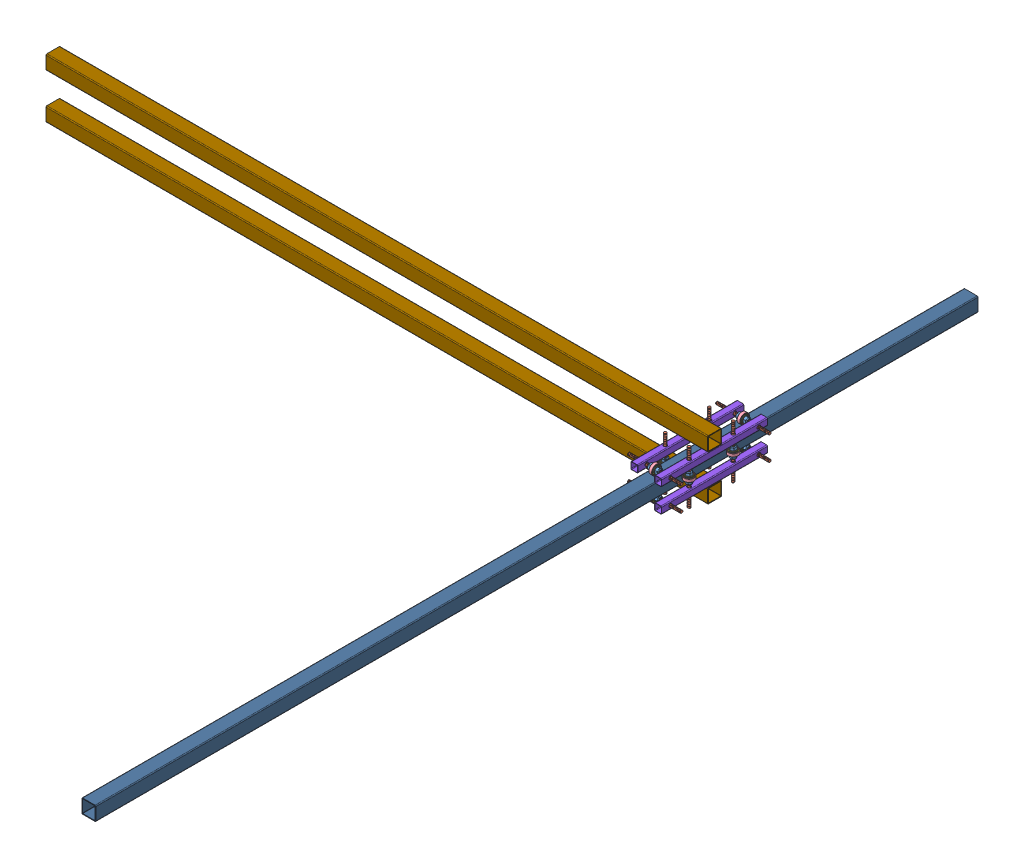
SolidWorks assembly CNC_SubAssembly1, configuration Default. Lengths in mm.
Overall size (1525 134 2000).
159 component instances, 10 part files, 35 mates.
Components (placement in the parent):
- BB_Rod_Assembly-1: BB_Rod_Assembly [Default] at (27 -60 -333.8942) x (-0.532809 0 0.846236) z (-0.846236 0 -0.532809) size (23.24 121.11 23.24)
  - M8_self_lock_Nut-1: M8_self_lock_Nut [Valor predeterminado] at (0 71 0) x (-0.837169 0 -0.546944) z (0 -1 0) size (15.1 12 8.06)
  - M8_Threaded_Rod-1: M8_Threaded_Rod [Default] at origin size (6.18 121.11 6.93)
  - M8_Washer-1: M8_Washer [Default] at (0 63.5 0) x (1 0 0) z (0 1 0) size (15.5 15.5 1.5)
  - BB_Assembly-1: BB_Assembly [Default] at (0 60 0) x (0 -1 0) z (-0.058052 0 0.998314) size (7 22 22)
    - BB_OuterRing-1: BB_OuterRing [Default] at origin size (7 22 22)
    - BB_InnerRing-1: BB_InnerRing [Default] x (1 0 0) z (0 0.97954 -0.20125) size (7 13 13)
    - BB_Ball-1: BB_Ball [Default] at (0 1.61 7.8363) x (-1 0 0) z (0 -0.97954 0.20125) size (4.5 4.5 4.5)
    - BB_Cage-1: BB_Cage [Default] x (0 -0.20125 -0.97954) z (1 0 0) size (18 18 2.77)
    - BB_Ball-2: BB_Ball [Default] at (0 6.6796 4.4027) x (-1 0 0) z (0 -0.550334 0.834945) size (4.5 4.5 4.5)
    - BB_Ball-3: BB_Ball [Default] at (0 7.8363 -1.61) x (-1 0 0) z (0 0.20125 0.97954) size (4.5 4.5 4.5)
    - BB_Ball-4: BB_Ball [Default] at (0 4.4027 -6.6796) x (-1 0 0) z (0 0.834945 0.550334) size (4.5 4.5 4.5)
    - BB_Ball-5: BB_Ball [Default] at (0 -1.61 -7.8363) x (-1 0 0) z (0 0.97954 -0.20125) size (4.5 4.5 4.5)
    - BB_Ball-6: BB_Ball [Default] at (0 -6.6796 -4.4027) x (-1 0 0) z (0 0.550334 -0.834945) size (4.5 4.5 4.5)
    - BB_Ball-7: BB_Ball [Default] at (0 -7.8363 1.61) x (-1 0 0) z (0 -0.20125 -0.97954) size (4.5 4.5 4.5)
    - BB_Ball-8: BB_Ball [Default] at (0 -4.4027 6.6796) x (-1 0 0) z (0 -0.834945 -0.550334) size (4.5 4.5 4.5)
    - BB_Cage-2: BB_Cage [Default] x (0 0.20125 0.97954) z (-1 0 0) size (18 18 2.77)
  - M8_Washer-3: M8_Washer [Default] at (0 55 0) x (1 0 0) z (0 1 0) size (15.5 15.5 1.5)
  - M8_self_lock_Nut-15: M8_self_lock_Nut [Valor predeterminado] at (0 49 0) x (1 0 0) z (0 1 0) size (15.1 12 8.06)
- Square_Tubing_16mm-1: Square_Tubing_16mm [Default] at (27 27 -383.8942) size (16 16 240)
- BB_Rod_Assembly-2: BB_Rod_Assembly [Default] at (27 -60 -433.8942) x (0.999895 0 -0.014471) z (0.014471 0 0.999895) size (23.24 121.11 23.24)
  - M8_self_lock_Nut-1: M8_self_lock_Nut [Valor predeterminado] at (0 71 0) x (-0.837169 0 -0.546944) z (0 -1 0) size (15.1 12 8.06)
  - M8_Threaded_Rod-1: M8_Threaded_Rod [Default] at origin size (6.18 121.11 6.93)
  - M8_Washer-1: M8_Washer [Default] at (0 63.5 0) x (1 0 0) z (0 1 0) size (15.5 15.5 1.5)
  - BB_Assembly-1: BB_Assembly [Default] at (0 60 0) x (0 -1 0) z (-0.058052 0 0.998314) size (7 22 22)
    - BB_OuterRing-1: BB_OuterRing [Default] at origin size (7 22 22)
    - BB_InnerRing-1: BB_InnerRing [Default] x (1 0 0) z (0 0.97954 -0.20125) size (7 13 13)
    - BB_Ball-1: BB_Ball [Default] at (0 1.61 7.8363) x (-1 0 0) z (0 -0.97954 0.20125) size (4.5 4.5 4.5)
    - BB_Cage-1: BB_Cage [Default] x (0 -0.20125 -0.97954) z (1 0 0) size (18 18 2.77)
    - BB_Ball-2: BB_Ball [Default] at (0 6.6796 4.4027) x (-1 0 0) z (0 -0.550334 0.834945) size (4.5 4.5 4.5)
    - BB_Ball-3: BB_Ball [Default] at (0 7.8363 -1.61) x (-1 0 0) z (0 0.20125 0.97954) size (4.5 4.5 4.5)
    - BB_Ball-4: BB_Ball [Default] at (0 4.4027 -6.6796) x (-1 0 0) z (0 0.834945 0.550334) size (4.5 4.5 4.5)
    - BB_Ball-5: BB_Ball [Default] at (0 -1.61 -7.8363) x (-1 0 0) z (0 0.97954 -0.20125) size (4.5 4.5 4.5)
    - BB_Ball-6: BB_Ball [Default] at (0 -6.6796 -4.4027) x (-1 0 0) z (0 0.550334 -0.834945) size (4.5 4.5 4.5)
    - BB_Ball-7: BB_Ball [Default] at (0 -7.8363 1.61) x (-1 0 0) z (0 -0.20125 -0.97954) size (4.5 4.5 4.5)
    - BB_Ball-8: BB_Ball [Default] at (0 -4.4027 6.6796) x (-1 0 0) z (0 -0.834945 -0.550334) size (4.5 4.5 4.5)
    - BB_Cage-2: BB_Cage [Default] x (0 0.20125 0.97954) z (-1 0 0) size (18 18 2.77)
  - M8_Washer-3: M8_Washer [Default] at (0 55 0) x (1 0 0) z (0 1 0) size (15.5 15.5 1.5)
  - M8_self_lock_Nut-15: M8_self_lock_Nut [Valor predeterminado] at (0 49 0) x (1 0 0) z (0 1 0) size (15.1 12 8.06)
- Square_Tubing_16mm-2: Square_Tubing_16mm [Default] at (27 -27 -383.8942) size (16 16 240)
- BB_Rod_Assembly-3: BB_Rod_Assembly [Default] at (-60 27 -483.8942) x (0 -0.853939 -0.520374) z (0 -0.520374 0.853939) size (23.24 121.11 23.24)
  - M8_self_lock_Nut-1: M8_self_lock_Nut [Valor predeterminado] at (0 71 0) x (-0.837169 0 -0.546944) z (0 -1 0) size (15.1 12 8.06)
  - M8_Threaded_Rod-1: M8_Threaded_Rod [Default] at origin size (6.18 121.11 6.93)
  - M8_Washer-1: M8_Washer [Default] at (0 63.5 0) x (1 0 0) z (0 1 0) size (15.5 15.5 1.5)
  - BB_Assembly-1: BB_Assembly [Default] at (0 60 0) x (0 -1 0) z (-0.058052 0 0.998314) size (7 22 22)
    - BB_OuterRing-1: BB_OuterRing [Default] at origin size (7 22 22)
    - BB_InnerRing-1: BB_InnerRing [Default] x (1 0 0) z (0 0.97954 -0.20125) size (7 13 13)
    - BB_Ball-1: BB_Ball [Default] at (0 1.61 7.8363) x (-1 0 0) z (0 -0.97954 0.20125) size (4.5 4.5 4.5)
    - BB_Cage-1: BB_Cage [Default] x (0 -0.20125 -0.97954) z (1 0 0) size (18 18 2.77)
    - BB_Ball-2: BB_Ball [Default] at (0 6.6796 4.4027) x (-1 0 0) z (0 -0.550334 0.834945) size (4.5 4.5 4.5)
    - BB_Ball-3: BB_Ball [Default] at (0 7.8363 -1.61) x (-1 0 0) z (0 0.20125 0.97954) size (4.5 4.5 4.5)
    - BB_Ball-4: BB_Ball [Default] at (0 4.4027 -6.6796) x (-1 0 0) z (0 0.834945 0.550334) size (4.5 4.5 4.5)
    - BB_Ball-5: BB_Ball [Default] at (0 -1.61 -7.8363) x (-1 0 0) z (0 0.97954 -0.20125) size (4.5 4.5 4.5)
    - BB_Ball-6: BB_Ball [Default] at (0 -6.6796 -4.4027) x (-1 0 0) z (0 0.550334 -0.834945) size (4.5 4.5 4.5)
    - BB_Ball-7: BB_Ball [Default] at (0 -7.8363 1.61) x (-1 0 0) z (0 -0.20125 -0.97954) size (4.5 4.5 4.5)
    - BB_Ball-8: BB_Ball [Default] at (0 -4.4027 6.6796) x (-1 0 0) z (0 -0.834945 -0.550334) size (4.5 4.5 4.5)
    - BB_Cage-2: BB_Cage [Default] x (0 0.20125 0.97954) z (-1 0 0) size (18 18 2.77)
  - M8_Washer-3: M8_Washer [Default] at (0 55 0) x (1 0 0) z (0 1 0) size (15.5 15.5 1.5)
  - M8_self_lock_Nut-15: M8_self_lock_Nut [Valor predeterminado] at (0 49 0) x (1 0 0) z (0 1 0) size (15.1 12 8.06)
- BB_Rod_Assembly-4: BB_Rod_Assembly [Default] at (-60 27 -283.8942) x (0 -0.092758 0.995689) z (0 0.995689 0.092758) size (23.24 121.11 23.24)
  - M8_self_lock_Nut-1: M8_self_lock_Nut [Valor predeterminado] at (0 71 0) x (-0.837169 0 -0.546944) z (0 -1 0) size (15.1 12 8.06)
  - M8_Threaded_Rod-1: M8_Threaded_Rod [Default] at origin size (6.18 121.11 6.93)
  - M8_Washer-1: M8_Washer [Default] at (0 63.5 0) x (1 0 0) z (0 1 0) size (15.5 15.5 1.5)
  - BB_Assembly-1: BB_Assembly [Default] at (0 60 0) x (0 -1 0) z (-0.058052 0 0.998314) size (7 22 22)
    - BB_OuterRing-1: BB_OuterRing [Default] at origin size (7 22 22)
    - BB_InnerRing-1: BB_InnerRing [Default] x (1 0 0) z (0 0.97954 -0.20125) size (7 13 13)
    - BB_Ball-1: BB_Ball [Default] at (0 1.61 7.8363) x (-1 0 0) z (0 -0.97954 0.20125) size (4.5 4.5 4.5)
    - BB_Cage-1: BB_Cage [Default] x (0 -0.20125 -0.97954) z (1 0 0) size (18 18 2.77)
    - BB_Ball-2: BB_Ball [Default] at (0 6.6796 4.4027) x (-1 0 0) z (0 -0.550334 0.834945) size (4.5 4.5 4.5)
    - BB_Ball-3: BB_Ball [Default] at (0 7.8363 -1.61) x (-1 0 0) z (0 0.20125 0.97954) size (4.5 4.5 4.5)
    - BB_Ball-4: BB_Ball [Default] at (0 4.4027 -6.6796) x (-1 0 0) z (0 0.834945 0.550334) size (4.5 4.5 4.5)
    - BB_Ball-5: BB_Ball [Default] at (0 -1.61 -7.8363) x (-1 0 0) z (0 0.97954 -0.20125) size (4.5 4.5 4.5)
    - BB_Ball-6: BB_Ball [Default] at (0 -6.6796 -4.4027) x (-1 0 0) z (0 0.550334 -0.834945) size (4.5 4.5 4.5)
    - BB_Ball-7: BB_Ball [Default] at (0 -7.8363 1.61) x (-1 0 0) z (0 -0.20125 -0.97954) size (4.5 4.5 4.5)
    - BB_Ball-8: BB_Ball [Default] at (0 -4.4027 6.6796) x (-1 0 0) z (0 -0.834945 -0.550334) size (4.5 4.5 4.5)
    - BB_Cage-2: BB_Cage [Default] x (0 0.20125 0.97954) z (-1 0 0) size (18 18 2.77)
  - M8_Washer-3: M8_Washer [Default] at (0 55 0) x (1 0 0) z (0 1 0) size (15.5 15.5 1.5)
  - M8_self_lock_Nut-15: M8_self_lock_Nut [Valor predeterminado] at (0 49 0) x (1 0 0) z (0 1 0) size (15.1 12 8.06)
- Square_Tubing_16mm-3: Square_Tubing_16mm [Default] at (-27 -27 -383.8942) size (16 16 240)
- Square_Tubing_16mm-4: Square_Tubing_16mm [Default] at (-27 27 -383.8942) size (16 16 240)
- BB_Rod_Assembly-5: BB_Rod_Assembly [Default] at (-60 -27 -483.8942) x (0 -1 0) z (0 0 1) size (23.24 121.11 23.24)
  - M8_self_lock_Nut-1: M8_self_lock_Nut [Valor predeterminado] at (0 71 0) x (-0.837169 0 -0.546944) z (0 -1 0) size (15.1 12 8.06)
  - M8_Threaded_Rod-1: M8_Threaded_Rod [Default] at origin size (6.18 121.11 6.93)
  - M8_Washer-1: M8_Washer [Default] at (0 63.5 0) x (1 0 0) z (0 1 0) size (15.5 15.5 1.5)
  - BB_Assembly-1: BB_Assembly [Default] at (0 60 0) x (0 -1 0) z (-0.058052 0 0.998314) size (7 22 22)
    - BB_OuterRing-1: BB_OuterRing [Default] at origin size (7 22 22)
    - BB_InnerRing-1: BB_InnerRing [Default] x (1 0 0) z (0 0.97954 -0.20125) size (7 13 13)
    - BB_Ball-1: BB_Ball [Default] at (0 1.61 7.8363) x (-1 0 0) z (0 -0.97954 0.20125) size (4.5 4.5 4.5)
    - BB_Cage-1: BB_Cage [Default] x (0 -0.20125 -0.97954) z (1 0 0) size (18 18 2.77)
    - BB_Ball-2: BB_Ball [Default] at (0 6.6796 4.4027) x (-1 0 0) z (0 -0.550334 0.834945) size (4.5 4.5 4.5)
    - BB_Ball-3: BB_Ball [Default] at (0 7.8363 -1.61) x (-1 0 0) z (0 0.20125 0.97954) size (4.5 4.5 4.5)
    - BB_Ball-4: BB_Ball [Default] at (0 4.4027 -6.6796) x (-1 0 0) z (0 0.834945 0.550334) size (4.5 4.5 4.5)
    - BB_Ball-5: BB_Ball [Default] at (0 -1.61 -7.8363) x (-1 0 0) z (0 0.97954 -0.20125) size (4.5 4.5 4.5)
    - BB_Ball-6: BB_Ball [Default] at (0 -6.6796 -4.4027) x (-1 0 0) z (0 0.550334 -0.834945) size (4.5 4.5 4.5)
    - BB_Ball-7: BB_Ball [Default] at (0 -7.8363 1.61) x (-1 0 0) z (0 -0.20125 -0.97954) size (4.5 4.5 4.5)
    - BB_Ball-8: BB_Ball [Default] at (0 -4.4027 6.6796) x (-1 0 0) z (0 -0.834945 -0.550334) size (4.5 4.5 4.5)
    - BB_Cage-2: BB_Cage [Default] x (0 0.20125 0.97954) z (-1 0 0) size (18 18 2.77)
  - M8_Washer-3: M8_Washer [Default] at (0 55 0) x (1 0 0) z (0 1 0) size (15.5 15.5 1.5)
  - M8_self_lock_Nut-15: M8_self_lock_Nut [Valor predeterminado] at (0 49 0) x (1 0 0) z (0 1 0) size (15.1 12 8.06)
- BB_Rod_Assembly-6: BB_Rod_Assembly [Default] at (-27 -60 -333.8942) x (0.666967 0 -0.745087) z (0.745087 0 0.666967) size (23.24 121.11 23.24)
  - M8_self_lock_Nut-1: M8_self_lock_Nut [Valor predeterminado] at (0 71 0) x (-0.837169 0 -0.546944) z (0 -1 0) size (15.1 12 8.06)
  - M8_Threaded_Rod-1: M8_Threaded_Rod [Default] at origin size (6.18 121.11 6.93)
  - M8_Washer-1: M8_Washer [Default] at (0 63.5 0) x (1 0 0) z (0 1 0) size (15.5 15.5 1.5)
  - BB_Assembly-1: BB_Assembly [Default] at (0 60 0) x (0 -1 0) z (-0.058052 0 0.998314) size (7 22 22)
    - BB_OuterRing-1: BB_OuterRing [Default] at origin size (7 22 22)
    - BB_InnerRing-1: BB_InnerRing [Default] x (1 0 0) z (0 0.97954 -0.20125) size (7 13 13)
    - BB_Ball-1: BB_Ball [Default] at (0 1.61 7.8363) x (-1 0 0) z (0 -0.97954 0.20125) size (4.5 4.5 4.5)
    - BB_Cage-1: BB_Cage [Default] x (0 -0.20125 -0.97954) z (1 0 0) size (18 18 2.77)
    - BB_Ball-2: BB_Ball [Default] at (0 6.6796 4.4027) x (-1 0 0) z (0 -0.550334 0.834945) size (4.5 4.5 4.5)
    - BB_Ball-3: BB_Ball [Default] at (0 7.8363 -1.61) x (-1 0 0) z (0 0.20125 0.97954) size (4.5 4.5 4.5)
    - BB_Ball-4: BB_Ball [Default] at (0 4.4027 -6.6796) x (-1 0 0) z (0 0.834945 0.550334) size (4.5 4.5 4.5)
    - BB_Ball-5: BB_Ball [Default] at (0 -1.61 -7.8363) x (-1 0 0) z (0 0.97954 -0.20125) size (4.5 4.5 4.5)
    - BB_Ball-6: BB_Ball [Default] at (0 -6.6796 -4.4027) x (-1 0 0) z (0 0.550334 -0.834945) size (4.5 4.5 4.5)
    - BB_Ball-7: BB_Ball [Default] at (0 -7.8363 1.61) x (-1 0 0) z (0 -0.20125 -0.97954) size (4.5 4.5 4.5)
    - BB_Ball-8: BB_Ball [Default] at (0 -4.4027 6.6796) x (-1 0 0) z (0 -0.834945 -0.550334) size (4.5 4.5 4.5)
    - BB_Cage-2: BB_Cage [Default] x (0 0.20125 0.97954) z (-1 0 0) size (18 18 2.77)
  - M8_Washer-3: M8_Washer [Default] at (0 55 0) x (1 0 0) z (0 1 0) size (15.5 15.5 1.5)
  - M8_self_lock_Nut-15: M8_self_lock_Nut [Valor predeterminado] at (0 49 0) x (1 0 0) z (0 1 0) size (15.1 12 8.06)
- BB_Rod_Assembly-7: BB_Rod_Assembly [Default] at (-60 -27 -283.8942) x (0 -0.99604 -0.08891) z (0 -0.08891 0.99604) size (23.24 121.11 23.24)
  - M8_self_lock_Nut-1: M8_self_lock_Nut [Valor predeterminado] at (0 71 0) x (-0.837169 0 -0.546944) z (0 -1 0) size (15.1 12 8.06)
  - M8_Threaded_Rod-1: M8_Threaded_Rod [Default] at origin size (6.18 121.11 6.93)
  - M8_Washer-1: M8_Washer [Default] at (0 63.5 0) x (1 0 0) z (0 1 0) size (15.5 15.5 1.5)
  - BB_Assembly-1: BB_Assembly [Default] at (0 60 0) x (0 -1 0) z (-0.058052 0 0.998314) size (7 22 22)
    - BB_OuterRing-1: BB_OuterRing [Default] at origin size (7 22 22)
    - BB_InnerRing-1: BB_InnerRing [Default] x (1 0 0) z (0 0.97954 -0.20125) size (7 13 13)
    - BB_Ball-1: BB_Ball [Default] at (0 1.61 7.8363) x (-1 0 0) z (0 -0.97954 0.20125) size (4.5 4.5 4.5)
    - BB_Cage-1: BB_Cage [Default] x (0 -0.20125 -0.97954) z (1 0 0) size (18 18 2.77)
    - BB_Ball-2: BB_Ball [Default] at (0 6.6796 4.4027) x (-1 0 0) z (0 -0.550334 0.834945) size (4.5 4.5 4.5)
    - BB_Ball-3: BB_Ball [Default] at (0 7.8363 -1.61) x (-1 0 0) z (0 0.20125 0.97954) size (4.5 4.5 4.5)
    - BB_Ball-4: BB_Ball [Default] at (0 4.4027 -6.6796) x (-1 0 0) z (0 0.834945 0.550334) size (4.5 4.5 4.5)
    - BB_Ball-5: BB_Ball [Default] at (0 -1.61 -7.8363) x (-1 0 0) z (0 0.97954 -0.20125) size (4.5 4.5 4.5)
    - BB_Ball-6: BB_Ball [Default] at (0 -6.6796 -4.4027) x (-1 0 0) z (0 0.550334 -0.834945) size (4.5 4.5 4.5)
    - BB_Ball-7: BB_Ball [Default] at (0 -7.8363 1.61) x (-1 0 0) z (0 -0.20125 -0.97954) size (4.5 4.5 4.5)
    - BB_Ball-8: BB_Ball [Default] at (0 -4.4027 6.6796) x (-1 0 0) z (0 -0.834945 -0.550334) size (4.5 4.5 4.5)
    - BB_Cage-2: BB_Cage [Default] x (0 0.20125 0.97954) z (-1 0 0) size (18 18 2.77)
  - M8_Washer-3: M8_Washer [Default] at (0 55 0) x (1 0 0) z (0 1 0) size (15.5 15.5 1.5)
  - M8_self_lock_Nut-15: M8_self_lock_Nut [Valor predeterminado] at (0 49 0) x (1 0 0) z (0 1 0) size (15.1 12 8.06)
- BB_Rod_Assembly-8: BB_Rod_Assembly [Default] at (-27 -60 -433.8942) x (0.999918 0 -0.012811) z (0.012811 0 0.999918) size (23.24 121.11 23.24)
  - M8_self_lock_Nut-1: M8_self_lock_Nut [Valor predeterminado] at (0 71 0) x (-0.837169 0 -0.546944) z (0 -1 0) size (15.1 12 8.06)
  - M8_Threaded_Rod-1: M8_Threaded_Rod [Default] at origin size (6.18 121.11 6.93)
  - M8_Washer-1: M8_Washer [Default] at (0 63.5 0) x (1 0 0) z (0 1 0) size (15.5 15.5 1.5)
  - BB_Assembly-1: BB_Assembly [Default] at (0 60 0) x (0 -1 0) z (-0.058052 0 0.998314) size (7 22 22)
    - BB_OuterRing-1: BB_OuterRing [Default] at origin size (7 22 22)
    - BB_InnerRing-1: BB_InnerRing [Default] x (1 0 0) z (0 0.97954 -0.20125) size (7 13 13)
    - BB_Ball-1: BB_Ball [Default] at (0 1.61 7.8363) x (-1 0 0) z (0 -0.97954 0.20125) size (4.5 4.5 4.5)
    - BB_Cage-1: BB_Cage [Default] x (0 -0.20125 -0.97954) z (1 0 0) size (18 18 2.77)
    - BB_Ball-2: BB_Ball [Default] at (0 6.6796 4.4027) x (-1 0 0) z (0 -0.550334 0.834945) size (4.5 4.5 4.5)
    - BB_Ball-3: BB_Ball [Default] at (0 7.8363 -1.61) x (-1 0 0) z (0 0.20125 0.97954) size (4.5 4.5 4.5)
    - BB_Ball-4: BB_Ball [Default] at (0 4.4027 -6.6796) x (-1 0 0) z (0 0.834945 0.550334) size (4.5 4.5 4.5)
    - BB_Ball-5: BB_Ball [Default] at (0 -1.61 -7.8363) x (-1 0 0) z (0 0.97954 -0.20125) size (4.5 4.5 4.5)
    - BB_Ball-6: BB_Ball [Default] at (0 -6.6796 -4.4027) x (-1 0 0) z (0 0.550334 -0.834945) size (4.5 4.5 4.5)
    - BB_Ball-7: BB_Ball [Default] at (0 -7.8363 1.61) x (-1 0 0) z (0 -0.20125 -0.97954) size (4.5 4.5 4.5)
    - BB_Ball-8: BB_Ball [Default] at (0 -4.4027 6.6796) x (-1 0 0) z (0 -0.834945 -0.550334) size (4.5 4.5 4.5)
    - BB_Cage-2: BB_Cage [Default] x (0 0.20125 0.97954) z (-1 0 0) size (18 18 2.77)
  - M8_Washer-3: M8_Washer [Default] at (0 55 0) x (1 0 0) z (0 1 0) size (15.5 15.5 1.5)
  - M8_self_lock_Nut-15: M8_self_lock_Nut [Valor predeterminado] at (0 49 0) x (1 0 0) z (0 1 0) size (15.1 12 8.06)
- 32mm_Square_Tubing_1.5M-3: 32mm_Square_Tubing_1.5M [Default] at (-715 51 -383.8942) x (0 0 -1) z (1 0 0) size (32 32 1500)
- 32mm_Square_Tubing_1.5M-4: 32mm_Square_Tubing_1.5M [Default] at (-715 -51 -383.8942) x (0 0 -1) z (1 0 0) size (32 32 1500)
- 32mm_Square_Tubing_2m-1: 32mm_Square_Tubing_2m [Default] at origin size (32 32 2000)
Mates (geometry in assembly coordinates):
- Concentric1: concentric anti-aligned: cylinder of BB_Rod_Assembly-1/M8_Threaded_Rod-1 through (27 60 -333.8942) axis (0 -1 0) radius 3; cylinder of Square_Tubing_16mm-1 through (27 19 -333.8942) axis (0 1 0) radius 4
- Concentric2: concentric anti-aligned: cylinder of Square_Tubing_16mm-1 through (27 19 -433.8942) axis (0 1 0) radius 4; cylinder of BB_Rod_Assembly-2/M8_Threaded_Rod-1 through (27 60 -433.8942) axis (0 -1 0) radius 3
- Concentric3: concentric anti-aligned: cylinder of BB_Rod_Assembly-1/M8_Threaded_Rod-1 through (27 60 -333.8942) axis (0 -1 0) radius 3; cylinder of Square_Tubing_16mm-2 through (27 -35 -333.8942) axis (0 1 0) radius 4
- Concentric4: concentric anti-aligned: cylinder of Square_Tubing_16mm-1 through (19 27 -283.8942) axis (1 0 0) radius 4; cylinder of BB_Rod_Assembly-4/M8_Threaded_Rod-1 through (60 27 -283.8942) axis (-1 0 0) radius 3
- Concentric5: concentric anti-aligned: cylinder of Square_Tubing_16mm-1 through (19 27 -483.8942) axis (1 0 0) radius 4; cylinder of BB_Rod_Assembly-3/M8_Threaded_Rod-1 through (60 27 -483.8942) axis (-1 0 0) radius 3
- Concentric6: concentric anti-aligned: cylinder of Square_Tubing_16mm-2 through (19 -27 -283.8942) axis (1 0 0) radius 4; cylinder of BB_Rod_Assembly-7/M8_Threaded_Rod-1 through (60 -27 -283.8942) axis (-1 0 0) radius 3
- Concentric7: concentric anti-aligned: cylinder of Square_Tubing_16mm-2 through (19 -27 -483.8942) axis (1 0 0) radius 4; cylinder of BB_Rod_Assembly-5/M8_Threaded_Rod-1 through (60 -27 -483.8942) axis (-1 0 0) radius 3
- Concentric8: concentric anti-aligned: cylinder of Square_Tubing_16mm-3 through (-35 -27 -283.8942) axis (1 0 0) radius 4; cylinder of BB_Rod_Assembly-7/M8_Threaded_Rod-1 through (60 -27 -283.8942) axis (-1 0 0) radius 3
- Concentric9: concentric anti-aligned: cylinder of BB_Rod_Assembly-4/M8_Threaded_Rod-1 through (60 27 -283.8942) axis (-1 0 0) radius 3; cylinder of Square_Tubing_16mm-4 through (-35 27 -283.8942) axis (1 0 0) radius 4
- Concentric10: concentric anti-aligned: cylinder of Square_Tubing_16mm-4 through (-27 19 -433.8942) axis (0 1 0) radius 4; cylinder of BB_Rod_Assembly-8/M8_Threaded_Rod-1 through (-27 60 -433.8942) axis (0 -1 0) radius 3
- Concentric11: concentric anti-aligned: cylinder of Square_Tubing_16mm-4 through (-27 19 -333.8942) axis (0 1 0) radius 4; cylinder of BB_Rod_Assembly-6/M8_Threaded_Rod-1 through (-27 60 -333.8942) axis (0 -1 0) radius 3
- Concentric12: concentric anti-aligned: cylinder of Square_Tubing_16mm-3 through (-27 -35 -333.8942) axis (0 1 0) radius 4; cylinder of BB_Rod_Assembly-6/M8_Threaded_Rod-1 through (-27 60 -333.8942) axis (0 -1 0) radius 3
- Coincident15: coincident anti-aligned: plane of Square_Tubing_16mm-2 through (21 -35 -503.8942) normal (0 -1 0); plane of 32mm_Square_Tubing_1.5M-4 through (-1465 -35 -369.8942) normal (0 1 0)
- Coincident16: coincident anti-aligned: plane of Square_Tubing_16mm-1 through (21 35 -503.8942) normal (0 1 0); plane of 32mm_Square_Tubing_1.5M-3 through (-1465 35 -369.8942) normal (0 -1 0)
- Width9: width anti-aligned: plane of 32mm_Square_Tubing_1.5M-3 through (-1465 37 -367.8942) normal (0 0 1); plane of 32mm_Square_Tubing_1.5M-3 through (-1465 37 -399.8942) normal (0 0 -1); plane of Square_Tubing_16mm-1 through (21 21 -503.8942) normal (0 0 -1); plane of Square_Tubing_16mm-1 through (21 21 -263.8942) normal (0 0 1)
- Width10: width aligned: plane of 32mm_Square_Tubing_1.5M-4 through (-1465 -65 -367.8942) normal (0 0 1); plane of 32mm_Square_Tubing_1.5M-4 through (-1465 -65 -399.8942) normal (0 0 -1); plane of Square_Tubing_16mm-2 through (21 -33 -263.8942) normal (0 0 1); plane of Square_Tubing_16mm-2 through (21 -33 -503.8942) normal (0 0 -1)
- Coincident20: coincident aligned: plane of Square_Tubing_16mm-1 through (35 21 -503.8942) normal (1 0 0); plane of 32mm_Square_Tubing_1.5M-3 through (35 37 -397.8942) normal (1 0 0)
- Coincident21: coincident aligned: plane of Square_Tubing_16mm-2 through (35 -33 -503.8942) normal (1 0 0); plane of 32mm_Square_Tubing_1.5M-4 through (35 -65 -397.8942) normal (1 0 0)
- Coincident22: coordinate: point of 32mm_Square_Tubing_2m-1
- Tangent1: tangent anti-aligned: cylinder of BB_Rod_Assembly-1/BB_Assembly-1/BB_OuterRing-1 through (27 29.8426 -333.8942) axis (0 1 0) radius 11; plane of 32mm_Square_Tubing_2m-1 through (16 -14 -1000) normal (1 0 0)
- Tangent2: tangent anti-aligned: cylinder of BB_Rod_Assembly-2/BB_Assembly-1/BB_OuterRing-1 through (27 29.8426 -433.8942) axis (0 1 0) radius 11; plane of 32mm_Square_Tubing_2m-1 through (16 -14 -1000) normal (1 0 0)
- Tangent3: tangent anti-aligned: cylinder of BB_Rod_Assembly-4/BB_Assembly-1/BB_OuterRing-1 through (29.8426 27 -283.8942) axis (1 0 0) radius 11; plane of 32mm_Square_Tubing_2m-1 through (-14 16 -1000) normal (0 1 0)
- Tangent4: tangent anti-aligned: cylinder of BB_Rod_Assembly-3/BB_Assembly-1/BB_OuterRing-1 through (29.8426 27 -483.8942) axis (1 0 0) radius 11; plane of 32mm_Square_Tubing_2m-1 through (-14 16 -1000) normal (0 1 0)
- Tangent5: tangent anti-aligned: cylinder of BB_Rod_Assembly-6/BB_Assembly-1/BB_OuterRing-1 through (-27 29.8426 -333.8942) axis (0 1 0) radius 11; plane of 32mm_Square_Tubing_2m-1 through (-16 -14 -1000) normal (-1 0 0)
- Tangent6: tangent anti-aligned: cylinder of BB_Rod_Assembly-8/BB_Assembly-1/BB_OuterRing-1 through (-27 29.8426 -433.8942) axis (0 1 0) radius 11; plane of 32mm_Square_Tubing_2m-1 through (-16 -14 -1000) normal (-1 0 0)
- Tangent7: tangent anti-aligned: cylinder of BB_Rod_Assembly-7/BB_Assembly-1/BB_OuterRing-1 through (29.8426 -27 -283.8942) axis (1 0 0) radius 11; plane of 32mm_Square_Tubing_2m-1 through (-14 -16 -1000) normal (0 -1 0)
- Tangent8: tangent anti-aligned: cylinder of BB_Rod_Assembly-5/BB_Assembly-1/BB_OuterRing-1 through (29.8426 -27 -483.8942) axis (1 0 0) radius 11; plane of 32mm_Square_Tubing_2m-1 through (-14 -16 -1000) normal (0 -1 0)
- Width11: width anti-aligned: plane of 32mm_Square_Tubing_2m-1 through (-14 16 -1000) normal (0 1 0); plane of BB_Rod_Assembly-1/BB_Assembly-1/BB_OuterRing-1 through (-14 -16 -1000) normal (0 -1 0); plane of 32mm_Square_Tubing_2m-1 through (21.4802 -3.5 -326.1623) normal (0 -1 0); plane of BB_Rod_Assembly-1/BB_Assembly-1/BB_OuterRing-1 through (21.4802 3.5 -326.1623) normal (0 1 0)
- Width12: width anti-aligned: plane of BB_Rod_Assembly-2/BB_Assembly-1/BB_OuterRing-1 through (36.491 3.5 -433.48) normal (0 1 0); plane of 32mm_Square_Tubing_2m-1 through (36.491 -3.5 -433.48) normal (0 -1 0); plane of BB_Rod_Assembly-2/BB_Assembly-1/BB_OuterRing-1 through (-14 -16 -1000) normal (0 -1 0); plane of 32mm_Square_Tubing_2m-1 through (-14 16 -1000) normal (0 1 0)
- Width13: width anti-aligned: plane of 32mm_Square_Tubing_2m-1 through (16 -14 -1000) normal (1 0 0); plane of BB_Rod_Assembly-3/BB_Assembly-1/BB_OuterRing-1 through (-16 -14 -1000) normal (-1 0 0); plane of 32mm_Square_Tubing_2m-1 through (-3.5 18.6143 -488.3584) normal (-1 0 0); plane of BB_Rod_Assembly-3/BB_Assembly-1/BB_OuterRing-1 through (3.5 18.6143 -488.3584) normal (1 0 0)
- Width14: width anti-aligned: plane of 32mm_Square_Tubing_2m-1 through (16 -14 -1000) normal (1 0 0); plane of BB_Rod_Assembly-4/BB_Assembly-1/BB_OuterRing-1 through (-16 -14 -1000) normal (-1 0 0); plane of 32mm_Square_Tubing_2m-1 through (-3.5 26.6694 -274.3999) normal (-1 0 0); plane of BB_Rod_Assembly-4/BB_Assembly-1/BB_OuterRing-1 through (3.5 26.6694 -274.3999) normal (1 0 0)
- Width15: width anti-aligned: plane of 32mm_Square_Tubing_2m-1 through (-16 -14 -1000) normal (-1 0 0); plane of BB_Rod_Assembly-7/BB_Assembly-1/BB_OuterRing-1 through (16 -14 -1000) normal (1 0 0); plane of 32mm_Square_Tubing_2m-1 through (3.5 -36.4955 -284.1881) normal (1 0 0); plane of BB_Rod_Assembly-7/BB_Assembly-1/BB_OuterRing-1 through (-3.5 -36.4955 -284.1881) normal (-1 0 0)
- Width16: width anti-aligned: plane of 32mm_Square_Tubing_2m-1 through (-16 -14 -1000) normal (-1 0 0); plane of BB_Rod_Assembly-5/BB_Assembly-1/BB_OuterRing-1 through (16 -14 -1000) normal (1 0 0); plane of 32mm_Square_Tubing_2m-1 through (3.5 -36.484 -483.3427) normal (1 0 0); plane of BB_Rod_Assembly-5/BB_Assembly-1/BB_OuterRing-1 through (-3.5 -36.484 -483.3427) normal (-1 0 0)
- Width17: width aligned: plane of BB_Rod_Assembly-8/BB_Assembly-1/BB_OuterRing-1 through (-17.5097 3.5 -433.4642) normal (0 1 0); plane of 32mm_Square_Tubing_2m-1 through (-17.5097 -3.5 -433.4642) normal (0 -1 0); plane of BB_Rod_Assembly-8/BB_Assembly-1/BB_OuterRing-1 through (-14 16 -1000) normal (0 1 0); plane of 32mm_Square_Tubing_2m-1 through (-14 -16 -1000) normal (0 -1 0)
- Width18: width aligned: plane of BB_Rod_Assembly-6/BB_Assembly-1/BB_OuterRing-1 through (-20.2636 -3.5 -340.5927) normal (0 -1 0); plane of 32mm_Square_Tubing_2m-1 through (-20.2636 3.5 -340.5927) normal (0 1 0); plane of BB_Rod_Assembly-6/BB_Assembly-1/BB_OuterRing-1 through (-14 -16 -1000) normal (0 -1 0); plane of 32mm_Square_Tubing_2m-1 through (-14 16 -1000) normal (0 1 0)
